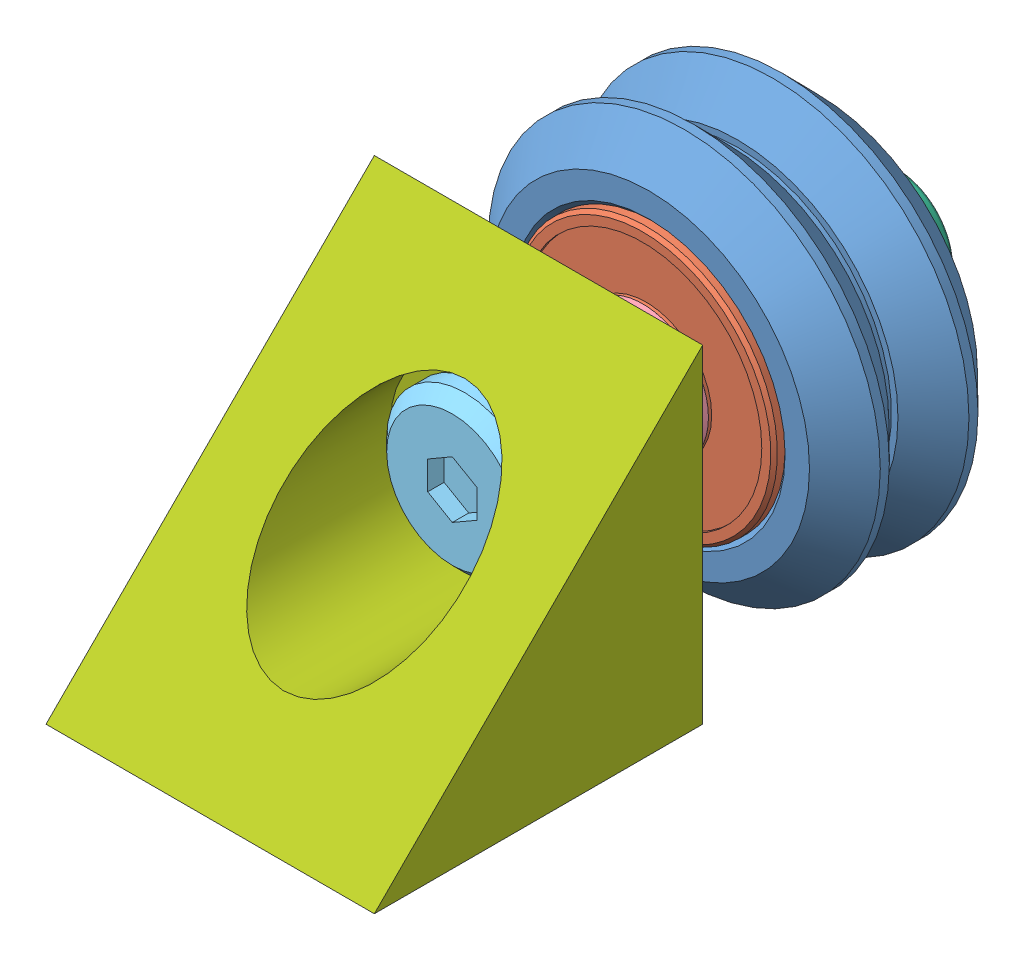
SolidWorks assembly V-Slot Delrin Dual Wheel Bracket Assembly1, configuration Default. Lengths in mm.
Overall size (23.89 23.89 41.95).
9 component instances, 7 part files, 2 mates.
Components (placement in the parent):
- V-Slot Delrin Dual Wheel Assembly-1: V-Slot Delrin Dual Wheel Assembly [3.5mm] at (15.5175 11.6249 16.7987) size (23.89 23.89 27.2)
  - Delrin Dual V-Wheel-1: Delrin Dual V-Wheel [Default] at (4.1766 13.0717 -11.0846) size (23.89 23.89 10.23)
  - Precision Ball Bearing-1: Precision Ball Bearing [Default] at (4.1766 13.0717 -8.0846) x (0 0 -1) z (1 0 0) size (5 16 16)
  - Precision Ball Bearing-2: Precision Ball Bearing [Default] at (4.1766 13.0717 -14.0846) x (0 0 -1) z (1 0 0) size (5 16 16)
  - 5mm Precision Washer-1: 5mm Precision Washer [Default] at (4.1766 13.0717 -11.5846) x (0 0 1) z (-1 0 0) size (1 10 10)
  - .25 Inch Aluminum Spacer-1: .25 Inch Aluminum Spacer [Default] at (4.1766 13.0717 0.7654) x (0 0 -1) z (1 0 0) size (6.35 8 8)
  - 5mm Low Profile Socket Head Screw - Multiple Lengths-1: 5mm Low Profile Socket Head Screw - Multiple Lengths [Default] at (4.1766 13.0717 6.0154) x (0 0 -1) z (1 0 0) size (27.2 9.5 9.5)
  - Nylon Insert Hex Locknut 5mm-1: Nylon Insert Hex Locknut 5mm [Default] at (4.1766 13.0717 -16.5846) x (-0.923728 -0.383049 0) z (0 0 -1) size (7.68 8.82 4.5)
- 90 Degree Angle Corner Connectr - V-Slot-1: 90 Degree Angle Corner Connectr - V-Slot [Default] at (19.6941 14.6966 17.564) x (0 0 1) z (-1 0 0) size (20 20 20)
Mates (geometry in assembly coordinates):
- Coincident1: coincident anti-aligned: plane of V-Slot Delrin Dual Wheel Assembly-1/5mm Low Profile Socket Head Screw - Multiple Lengths-1 through (19.6941 27.1966 21.064) normal (0 0 -1); plane of 90 Degree Angle Corner Connectr - V-Slot-1 through (29.6941 14.6966 21.064) normal (0 0 1)
- Concentric1: concentric aligned: cylinder of V-Slot Delrin Dual Wheel Assembly-1/.25 Inch Aluminum Spacer-1 through (19.6941 24.6966 11.214) axis (0 0 1) radius 4; cylinder of 90 Degree Angle Corner Connectr - V-Slot-1 through (19.6941 24.6966 17.564) axis (0 0 1) radius 3.57
